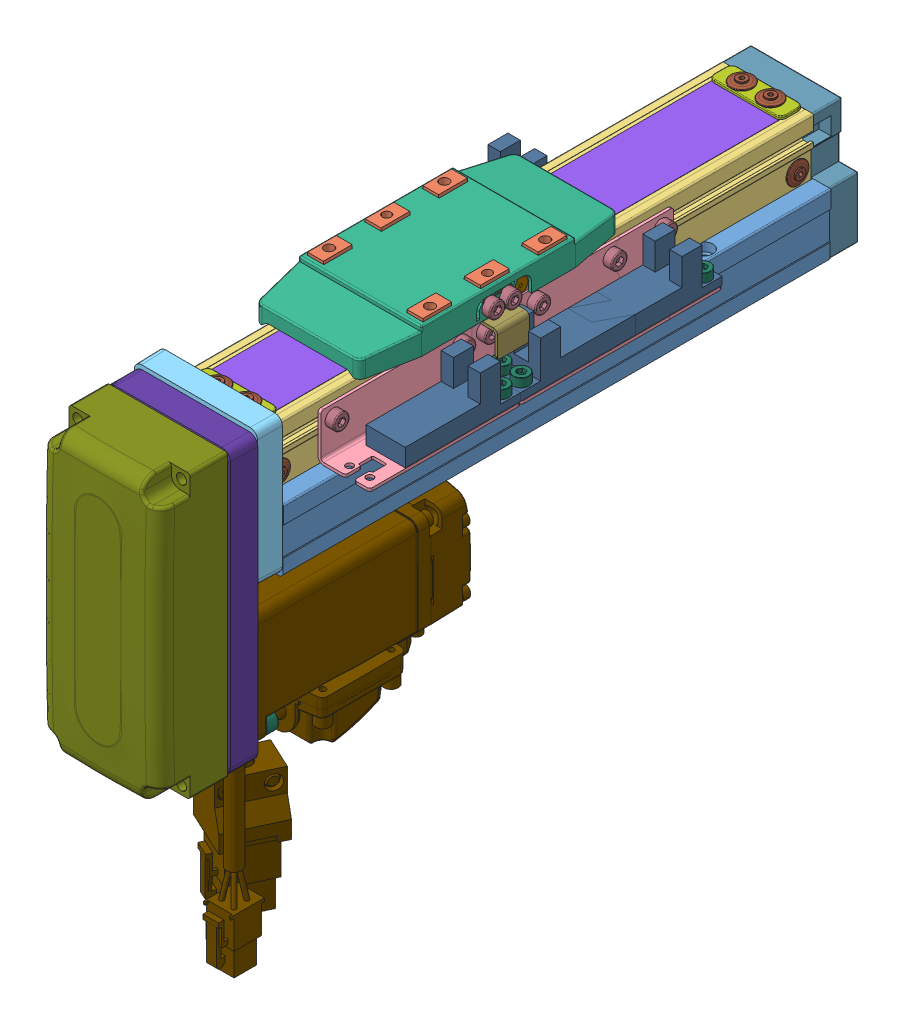
SolidWorks assembly G4-BM-100W, configuration 默认. Lengths in mm.
Overall size (67.76 184.1 242.95).
59 component instances, 18 part files, 48 mates.
Components (placement in the parent):
- 复件 底座GY4+140^G4-BM-100W-1: 复件 底座GY4+140^G4-BM-100W [默认] at (-6.4941 12.4482 0) x (-1 0 0) z (0 -1 0) size (44 190 22.05) (virtual)
- 复件 滑台G4^G4-BM-100W-1: 复件 滑台G4^G4-BM-100W [默认] at (2.1217 9 -75.2304) x (-1 0 0) z (0 0 -1) size (40 11.99 50) (virtual)
- 复件 侧盖G4+140^G4-BM-100W-1: 复件 侧盖G4+140^G4-BM-100W [默认] at (5.1767 14.25 0) x (-1 0 0) z (0 0 -1) size (8.3 20.5 190) (virtual)
- 复件 304开关座片G5-12^G4-BM-100W-1: 复件 304开关座片G5-12^G4-BM-100W [Default] at (5.9767 22.8 -18) x (0 0 -1) z (1 0 0) size (52.5 16 18) (virtual)
- 复件 丝杆座板GY4^G4-BM-100W-1: 复件 丝杆座板GY4^G4-BM-100W [默认] at (-9.9033 25 0) x (-1 0 0) z (0 0 -1) size (43 47.4 8.5) (virtual)
- 复件 滑台盖G4^G4-BM-100W-1: 复件 滑台盖G4^G4-BM-100W [默认] at (-9.9033 42.1 -120.2304) x (0 0 1) z (0 -1 0) size (90 42.6 9) (virtual)
- 复件 304钢带压片G4^G4-BM-100W-1: 复件 304钢带压片G4^G4-BM-100W [默认] at (-9.9033 41.6 -186) x (-1 0 0) z (0 0 -1) size (25 1 8) (virtual)
- 复件 钢带G4+140^G4-BM-100W-1: 复件 钢带G4+140^G4-BM-100W [Default] at (-20.8433 41.5 -581.114) x (0 0 -1) z (0 1 0) size (190 23.5 0.1) (virtual)
- 复件 304钢带压片G4^G4-BM-100W-2: 复件 304钢带压片G4^G4-BM-100W [默认] at (-9.9033 41.6 -4) x (-1 0 0) z (0 0 -1) size (25 1 8) (virtual)
- 复件 弹子油杯D5x5.5^G4-BM-100W-1: 复件 弹子油杯D5x5.5^G4-BM-100W [默认] at (-30.3783 45.5 -83.7304) x (0 0.72753 0.686076) z (1 0 0) size (5 5 5.73) (virtual)
- 复件 弹子油杯D5x5.5^G4-BM-100W-2: 复件 弹子油杯D5x5.5^G4-BM-100W [默认] at (10.6217 45.5 -83.7304) x (0 0.972647 -0.232289) z (-1 0 0) size (5 5 5.73) (virtual)
- 复件 光电开关EE-SX674^G4-BM-100W-1: 复件 光电开关EE-SX674^G4-BM-100W [默认] at (10.1767 23.8 -30.5) x (0 0 -1) z (1 0 0) size (40 15.5 13.6) (virtual)
- 复件 不锈钢内六角定制螺丝M3X7^G4-BM-100W-1: 复件 不锈钢内六角定制螺丝M3X7^G4-BM-100W [默认] at (-4.9033 42.9733 -4) x (0.724639 0 -0.689128) z (0 -1 0) size (7.67 7.67 6.5) (virtual)
- 复件 不锈钢内六角定制螺丝M3X7^G4-BM-100W-2: 复件 不锈钢内六角定制螺丝M3X7^G4-BM-100W [默认] at (-14.9033 42.9733 -4) x (0.264221 0 -0.964462) z (0 -1 0) size (7.67 7.67 6.5) (virtual)
- 复件 不锈钢内六角定制螺丝M3X7^G4-BM-100W-3: 复件 不锈钢内六角定制螺丝M3X7^G4-BM-100W [默认] at (-4.9033 42.9733 -186) x (-0.045987 0 0.998942) z (0 -1 0) size (7.67 7.67 6.5) (virtual)
- 复件 不锈钢内六角定制螺丝M3X7^G4-BM-100W-4: 复件 不锈钢内六角定制螺丝M3X7^G4-BM-100W [默认] at (-14.9033 42.9733 -186) x (0.70866 0 0.705551) z (0 -1 0) size (7.67 7.67 6.5) (virtual)
- 复件 不锈钢内六角定制螺丝M3X7^G4-BM-100W-5: 复件 不锈钢内六角定制螺丝M3X7^G4-BM-100W [默认] at (5.55 26.15 -5) x (0 0.645926 0.7634) z (-1 0 0) size (7.67 7.67 6.5) (virtual)
- 复件 不锈钢内六角定制螺丝M3X7^G4-BM-100W-6: 复件 不锈钢内六角定制螺丝M3X7^G4-BM-100W [默认] at (5.55 26.15 -185) x (0 0.430934 0.902383) z (-1 0 0) size (7.67 7.67 6.5) (virtual)
- 复件 不锈钢内六角定制螺丝M3X7^G4-BM-100W-7: 复件 不锈钢内六角定制螺丝M3X7^G4-BM-100W [默认] at (-25.3602 26.15 -185) x (0 -0.999999 -0.001479) z (1 0 0) size (7.67 7.67 6.5) (virtual)
- 复件 不锈钢内六角定制螺丝M3X7^G4-BM-100W-8: 复件 不锈钢内六角定制螺丝M3X7^G4-BM-100W [默认] at (-25.3565 26.15 -5) x (0 -1 0) z (1 0 0) size (7.67 7.67 6.5) (virtual)
- 复件 304感应片G5^G4-BM-100W-1: 复件 304感应片G5^G4-BM-100W [默认] at (15.6217 33 -80.7304) x (0 1 0) z (0 0 1) size (15 6.5 11) (virtual)
- hexagon socket head cap screws gb-32: hexagon socket head cap screws gb [GB_FASTENER_SCREWS_HSHCS M3X6-N] at (14.1217 45.5 -78.2304) x (-1 0 0) z (0 -0.928252 -0.371951) size (9 5.5 5.5)
- 复件 光电开关EE-SX674^G4-BM-100W-15: 复件 光电开关EE-SX674^G4-BM-100W [默认] at (23.7767 23.8 -110.5) x (0 0 1) z (-1 0 0) size (40 15.5 13.6) (virtual)
- 复件 304开关座片G5-12^G4-BM-100W-11: 复件 304开关座片G5-12^G4-BM-100W [Default] at (5.9767 22.8 -70.5) x (0 0 -1) z (1 0 0) size (52.5 16 18) (virtual)
- 复件 304开关座片G5-12^G4-BM-100W-10: 复件 304开关座片G5-12^G4-BM-100W [Default] at (5.9767 22.8 -88) x (0 0 -1) z (1 0 0) size (52.5 16 18) (virtual)
- 复件 轴承端盖G4(机加件)^G4-BM-100W-1: 复件 轴承端盖G4(机加件)^G4-BM-100W [默认] at (-9.9033 11.9 -190) x (0 0 -1) z (1 0 0) size (10 40.8 43) (virtual)
- hexagon socket head cap screws gb-33: hexagon socket head cap screws gb [GB_FASTENER_SCREWS_HSHCS M3X6-N] at (14.1217 45.5 -72.2304) x (-1 0 0) z (0 -0.928252 -0.371951) size (9 5.5 5.5)
- hexagon socket head cap screws gb-34: hexagon socket head cap screws gb [GB_FASTENER_SCREWS_HSHCS M3X6-N] at (-33.8783 45.5 -78.2304) x (1 0 0) z (0 0.928252 0.371951) size (9 5.5 5.5)
- hexagon socket head cap screws gb-35: hexagon socket head cap screws gb [GB_FASTENER_SCREWS_HSHCS M3X6-N] at (-33.8783 45.5 -72.2304) x (1 0 0) z (0 0.928252 0.371951) size (9 5.5 5.5)
- 复件 侧盖G4+140^G4-BM-100W-5: 复件 侧盖G4+140^G4-BM-100W [默认] at (-24.9833 14.25 -190) size (8.3 20.5 190) (virtual)
- 复件 光电开关EE-SX674^G4-BM-100W-14: 复件 光电开关EE-SX674^G4-BM-100W [默认] at (10.1767 23.8 -100.5) x (0 0 -1) z (1 0 0) size (40 15.5 13.6) (virtual)
- 复件 光电开关EE-SX674^G4-BM-100W-16: 复件 光电开关EE-SX674^G4-BM-100W [默认] at (-43.5833 23.8 -100.5) x (0 0 -1) z (1 0 0) size (40 15.5 13.6) (virtual)
- 复件 304开关座片G5-12^G4-BM-100W-14: 复件 304开关座片G5-12^G4-BM-100W [Default] at (-25.7833 22.8 -140.5) x (0 0 1) z (-1 0 0) size (52.5 16 18) (virtual)
- 复件 304感应片G5^G4-BM-100W-4: 复件 304感应片G5^G4-BM-100W [默认] at (-35.3783 33 -69.7304) x (0 1 0) z (0 0 -1) size (15 6.5 11) (virtual)
- hexagon socket head cap screws gb-36: hexagon socket head cap screws gb [GB_FASTENER_SCREWS_HSHCS M3X6-N] at (-26.4033 5.05 -199.6) x (0 0 1) z (-0.891634 -0.452757 0) size (9 5.5 5.5)
- hexagon socket head cap screws gb-37: hexagon socket head cap screws gb [GB_FASTENER_SCREWS_HSHCS M3X6-N] at (6.5967 5.05 -199.6) x (0 0 1) z (-0.891634 -0.452757 0) size (9 5.5 5.5)
- hexagon socket head cap screws gb-38: hexagon socket head cap screws gb [GB_FASTENER_SCREWS_HSHCS M3X6-N] at (-26.4033 18.05 -199.6) x (0 0 1) z (-0.891634 -0.452757 0) size (9 5.5 5.5)
- hexagon socket head cap screws gb-39: hexagon socket head cap screws gb [GB_FASTENER_SCREWS_HSHCS M3X6-N] at (6.5967 18.05 -199.6) x (0 0 1) z (-0.891634 -0.452757 0) size (9 5.5 5.5)
- hexagon socket head cap screws gb-41: hexagon socket head cap screws gb [GB_FASTENER_SCREWS_HSHCS M3X6-N] at (9.9767 34.8 -22.25) x (-1 0 0) z (0 -0.928252 -0.371951) size (9 5.5 5.5)
- hexagon socket head cap screws gb-42: hexagon socket head cap screws gb [GB_FASTENER_SCREWS_HSHCS M3X6-N] at (9.9767 34.8 -66.25) x (-1 0 0) z (0 -0.928252 -0.371951) size (9 5.5 5.5)
- hexagon socket head cap screws gb-43: hexagon socket head cap screws gb [GB_FASTENER_SCREWS_HSHCS M3X6-N] at (9.9767 34.8 -74.75) x (-1 0 0) z (0 0.928252 -0.371951) size (9 5.5 5.5)
- hexagon socket head cap screws gb-44: hexagon socket head cap screws gb [GB_FASTENER_SCREWS_HSHCS M3X6-N] at (9.9767 34.8 -118.75) x (-1 0 0) z (0 0.928252 -0.371951) size (9 5.5 5.5)
- hexagon socket head cap screws gb-45: hexagon socket head cap screws gb [GB_FASTENER_SCREWS_HSHCS M3X6-N] at (9.9767 34.8 -92.25) x (-1 0 0) z (0 -0.928252 -0.371951) size (9 5.5 5.5)
- hexagon socket head cap screws gb-46: hexagon socket head cap screws gb [GB_FASTENER_SCREWS_HSHCS M3X6-N] at (9.9767 34.8 -136.25) x (-1 0 0) z (0 -0.928252 -0.371951) size (9 5.5 5.5)
- hexagon socket head cap screws gb-47: hexagon socket head cap screws gb [GB_FASTENER_SCREWS_HSHCS M3X6-N] at (-29.7833 34.8 -136.25) x (1 0 0) z (0 0.928252 0.371951) size (9 5.5 5.5)
- hexagon socket head cap screws gb-48: hexagon socket head cap screws gb [GB_FASTENER_SCREWS_HSHCS M3X6-N] at (-29.7833 34.8 -92.25) x (1 0 0) z (0 0.928252 0.371951) size (9 5.5 5.5)
- socket head cap screw_iso-2: socket head cap screw_iso [ISO 4762 M3 x 5 --- 5N] at (13.4767 29.4 -67) x (0 -1 0) z (0 0 1) size (8 5.5 5.5)
- socket head cap screw_iso-3: socket head cap screw_iso [ISO 4762 M3 x 5 --- 5N] at (20.4767 29.4 -67) x (0 -1 0) z (0 0 1) size (8 5.5 5.5)
- socket head cap screw_iso-5: socket head cap screw_iso [ISO 4762 M4 x 12 --- 12N] at (-26.1667 -12.3383 -0.5) x (0 0 1) z (-0.923728 -0.383049 0) size (16 7 7)
- socket head cap screw_iso-6: socket head cap screw_iso [ISO 4762 M4 x 12 --- 12N] at (6.3602 -44.8652 -0.5) x (0 0 1) z (-0.815687 0.578493 0) size (16 7 7)
- socket head cap screw_iso-7: socket head cap screw_iso [ISO 4762 M3 x 5 --- 5N] at (20.4767 29.4 -74) x (0 -1 0) z (0 0 1) size (8 5.5 5.5)
- socket head cap screw_iso-8: socket head cap screw_iso [ISO 4762 M3 x 5 --- 5N] at (13.4767 29.4 -74) x (0 -1 0) z (0 0 1) size (8 5.5 5.5)
- socket head cap screw_iso-9: socket head cap screw_iso [ISO 4762 M3 x 5 --- 5N] at (13.4767 29.4 -137) x (0 -1 0) z (0 0 1) size (8 5.5 5.5)
- socket head cap screw_iso-10: socket head cap screw_iso [ISO 4762 M3 x 5 --- 5N] at (20.4767 29.4 -137) x (0 -1 0) z (0 0 1) size (8 5.5 5.5)
- socket head cap screw_iso-11: socket head cap screw_iso [ISO 4762 M3 x 5 --- 5N] at (-33.2833 29.4 -137) x (0 -1 0) z (0 0 -1) size (8 5.5 5.5)
- socket head cap screw_iso-12: socket head cap screw_iso [ISO 4762 M3 x 5 --- 5N] at (-40.2833 29.4 -137) x (0 -1 0) z (0 0 -1) size (8 5.5 5.5)
- 复件 同步轮罩壳G4^G4-BM-100W-1: 复件 同步轮罩壳G4^G4-BM-100W [默认] at (-9.9033 -2.3518 41.5) x (0 1 0) z (-1 0 0) size (98.56 24.45 42.56) (virtual)
- 复件 电机板G4-BLRM-P38^G4-BM-100W-1: 复件 电机板G4-BLRM-P38^G4-BM-100W [Default] at (-9.9033 -2.3518 -4.5) x (0 0 -1) z (1 0 0) size (10 98 43) (virtual)
- 复件 台达100W电机ECM-B3L-C20401RS1^G4-BM-100W-1: 复件 台达100W电机ECM-B3L-C20401RS1^G4-BM-100W [Default] at (-9.9033 -28.6018 3.5) x (-1 0 0) z (0 0 1) size (53.15 124.71 102.71) (virtual)
Mates (geometry in assembly coordinates):
- 重合86: coincident: plane of 复件 滑台G4^G4-BM-100W-1 through (-29.8783 50 -60.2304) normal (0 1 0); plane of 复件 滑台盖G4^G4-BM-100W-1 through (-31.2033 50 -101.4804) normal (0 -1 0)
- 同心50: concentric: cylinder of 复件 滑台G4^G4-BM-100W-1 through (-29.8783 45.5 -83.7304) axis (-1 0 0) radius 2.5; cylinder of 复件 弹子油杯D5x5.5^G4-BM-100W-1 through (-24.8783 45.5 -83.7304) axis (-1 0 0) radius 2.5
- 重合98: coincident: plane of 复件 滑台G4^G4-BM-100W-1 through (-24.8783 45.5 -83.7304) normal (-1 0 0); circle of 复件 弹子油杯D5x5.5^G4-BM-100W-1
- 同心51: concentric: cylinder of 复件 滑台G4^G4-BM-100W-1 through (10.1217 45.5 -83.7304) axis (1 0 0) radius 2.5; cylinder of 复件 弹子油杯D5x5.5^G4-BM-100W-2 through (5.1217 45.5 -83.7304) axis (1 0 0) radius 2.5
- 重合99: coincident: plane of 复件 滑台G4^G4-BM-100W-1 through (5.1217 45.5 -83.7304) normal (1 0 0); circle of 复件 弹子油杯D5x5.5^G4-BM-100W-2
- 重合127: coincident: plane of 复件 304钢带压片G4^G4-BM-100W-1 through (0.5967 42.6 -184) normal (0 1 0); circle of 复件 不锈钢内六角定制螺丝M3X7^G4-BM-100W-3
- 重合128: coincident: plane of 复件 304钢带压片G4^G4-BM-100W-1 through (0.5967 42.6 -184) normal (0 1 0); circle of 复件 不锈钢内六角定制螺丝M3X7^G4-BM-100W-4
- 同心86: concentric: circle of 复件 侧盖G4+140^G4-BM-100W-1; cylinder of 复件 不锈钢内六角定制螺丝M3X7^G4-BM-100W-6 through (0.07 26.15 -185) axis (1 0 0) radius 1.5
- 重合133: coincident: plane of 复件 侧盖G4+140^G4-BM-100W-1 through (5.1767 30.4257 -190) normal (1 0 0); circle of 复件 不锈钢内六角定制螺丝M3X7^G4-BM-100W-6
- 重合150: coincident: plane of 复件 滑台G4^G4-BM-100W-1 through (10.1217 42.5 -100.2304) normal (1 0 0); plane of 复件 304感应片G5^G4-BM-100W-1 through (10.1217 41 -69.7304) normal (-1 0 0)
- 同心103: concentric: cylinder of 复件 滑台G4^G4-BM-100W-1 through (10.1217 45.5 -78.2304) axis (1 0 0) radius 1.25; cylinder of 复件 304感应片G5^G4-BM-100W-1 through (10.1217 45.5 -78.2304) axis (-1 0 0) radius 1.7
- 同心104: concentric: cylinder of 复件 滑台G4^G4-BM-100W-1 through (10.1217 45.5 -72.2304) axis (1 0 0) radius 1.25; cylinder of 复件 304感应片G5^G4-BM-100W-1 through (10.1217 45.5 -72.2304) axis (-1 0 0) radius 1.7
- 同心105: concentric: cylinder of 复件 滑台G4^G4-BM-100W-1 through (10.1217 45.5 -78.2304) axis (1 0 0) radius 1.25; cylinder of hexagon socket head cap screws gb-32 through (5.1217 45.5 -78.2304) axis (1 0 0) radius 1.5
- 重合154: coincident: plane of 复件 304感应片G5^G4-BM-100W-1 through (11.1217 41 -69.7304) normal (1 0 0); plane of hexagon socket head cap screws gb-32 through (11.1217 45.5 -78.2304) normal (-1 0 0)
- 宽度8: width: plane of 复件 滑台盖G4^G4-BM-100W-1 through (-30.1033 42.1 -80.2804) normal (0 0 1); plane of 复件 滑台盖G4^G4-BM-100W-1 through (-30.1033 42.1 -70.1804) normal (0 0 -1); plane of 复件 滑台G4^G4-BM-100W-1 through (-29.8783 52 -70.2304) normal (0 0 1); plane of 复件 滑台G4^G4-BM-100W-1 through (-29.8783 52 -80.2304) normal (0 0 -1)
- 宽度9: width: plane of 复件 滑台G4^G4-BM-100W-1 through (-24.3783 48 -100.2304) normal (1 0 0); plane of 复件 滑台G4^G4-BM-100W-1 through (-29.8783 52 -100.2304) normal (-1 0 0); plane of 复件 滑台盖G4^G4-BM-100W-1 through (-24.1533 42.1 -70.1804) normal (-1 0 0); plane of 复件 滑台盖G4^G4-BM-100W-1 through (-30.1033 50.6 -101.4804) normal (1 0 0)
- 重合171: coincident: plane of 复件 底座GY4+140^G4-BM-100W-1 through (-31.4033 21.55 -190) normal (0 0 -1); plane of 复件 轴承端盖G4(机加件)^G4-BM-100W-1 through (-9.9033 11.9 -190) normal (0 0 1)
- 宽度10: width: plane of 复件 底座GY4+140^G4-BM-100W-1 through (12.0967 21.55 -190) normal (1 0 0); plane of 复件 底座GY4+140^G4-BM-100W-1 through (-31.9033 16.05 -190) normal (-1 0 0); plane of 复件 滑台盖G4^G4-BM-100W-1 through (-31.2033 50.6 -101.4804) normal (-1 0 0); plane of 复件 滑台盖G4^G4-BM-100W-1 through (11.3967 50.6 -101.4804) normal (1 0 0)
- 距离4: distance = 52 mm: plane of 复件 滑台G4^G4-BM-100W-1 through (-24.3783 52 -100.2304) normal (0 1 0); plane of 复件 底座GY4+140^G4-BM-100W-1 through (15.1408 0 0) normal (0 -1 0)
- 重合187: coincident: plane of 复件 底座GY4+140^G4-BM-100W-1 through (-31.4033 6.05 -190) normal (-1 0 0); plane of 复件 轴承端盖G4(机加件)^G4-BM-100W-1 through (-31.4033 11.9 -200) normal (-1 0 0)
- 同心117: concentric: cylinder of 复件 不锈钢内六角定制螺丝M3X7^G4-BM-100W-7 through (-19.8802 26.15 -185) axis (-1 0 0) radius 1.5; cylinder of 复件 侧盖G4+140^G4-BM-100W-5 through (-24.9833 26.15 -185) axis (-1 0 0) radius 1.5
- 相切3: tangent: torus of 复件 不锈钢内六角定制螺丝M3X7^G4-BM-100W-7; plane of 复件 侧盖G4+140^G4-BM-100W-5 through (-24.9833 30.4257 0) normal (-1 0 0)
- 重合189: coincident: plane of 复件 304钢带压片G4^G4-BM-100W-1 through (0.5967 41.6 -184) normal (0 -1 0); plane of 复件 钢带G4+140^G4-BM-100W-1 through (-20.8433 41.6 -581.114) normal (0 1 0)
- 同心118: concentric: cylinder of 复件 304钢带压片G4^G4-BM-100W-1 through (-4.9033 42.6 -186) axis (0 -1 0) radius 1.65; cylinder of 复件 不锈钢内六角定制螺丝M3X7^G4-BM-100W-3 through (-4.9033 37.4933 -186) axis (0 1 0) radius 1.5
- 同心119: concentric: cylinder of 复件 304钢带压片G4^G4-BM-100W-1 through (-14.9033 42.6 -186) axis (0 -1 0) radius 1.65; cylinder of 复件 不锈钢内六角定制螺丝M3X7^G4-BM-100W-4 through (-14.9033 37.4933 -186) axis (0 1 0) radius 1.5
- 重合190: coincident: plane of 复件 304钢带压片G4^G4-BM-100W-1 through (0.5967 42.6 -190) normal (0 0 -1); plane of 复件 轴承端盖G4(机加件)^G4-BM-100W-1 through (-9.9033 11.9 -190) normal (0 0 1)
- 宽度11: width: plane of 复件 304钢带压片G4^G4-BM-100W-1 through (-22.4033 42.6 -184) normal (-1 0 0); plane of 复件 304钢带压片G4^G4-BM-100W-1 through (2.5967 42.6 -184) normal (1 0 0); plane of 复件 侧盖G4+140^G4-BM-100W-1 through (5.9767 41.05 -190) normal (1 0 0); plane of 复件 侧盖G4+140^G4-BM-100W-5 through (-25.7833 41.05 0) normal (-1 0 0)
- 重合191: coincident: plane of 复件 轴承端盖G4(机加件)^G4-BM-100W-1 through (-26.4033 6.75 -196.6) normal (0 0 -1); plane of hexagon socket head cap screws gb-36 through (-26.4033 5.05 -196.6) normal (0 0 1)
- 同心121: concentric: cylinder of 复件 轴承端盖G4(机加件)^G4-BM-100W-1 through (-26.4033 5.05 -200) axis (0 0 -1) radius 1.7; cylinder of hexagon socket head cap screws gb-36 through (-26.4033 5.05 -190.6) axis (0 0 -1) radius 1.5
- 重合193: coincident: plane of 复件 304开关座片G5-12^G4-BM-100W-1 through (6.9767 40.8 -70.5) normal (1 0 0); plane of hexagon socket head cap screws gb-41 through (6.9767 34.8 -22.25) normal (-1 0 0)
- 同心123: concentric: cylinder of 复件 304开关座片G5-12^G4-BM-100W-1 through (5.9767 34.8 -22.25) axis (1 0 0) radius 1.6; cylinder of hexagon socket head cap screws gb-41 through (0.9767 34.8 -22.25) axis (1 0 0) radius 1.5
- 同心126: concentric: cylinder of 复件 光电开关EE-SX674^G4-BM-100W-1 through (13.4767 12.8 -67) axis (0 1 0) radius 1.75; cylinder of socket head cap screw_iso-2 through (13.4767 61.15 -67) axis (0 1 0) radius 2.75
- 重合196: coincident: plane of 复件 光电开关EE-SX674^G4-BM-100W-1 through (23.7767 26.4 -63.5) normal (0 1 0); plane of socket head cap screw_iso-2 through (16.2267 26.4 -67) normal (0 -1 0)
- 同心127: concentric: cylinder of 复件 光电开关EE-SX674^G4-BM-100W-1 through (20.4767 12.8 -67) axis (0 1 0) radius 1.75; cylinder of socket head cap screw_iso-3 through (20.4767 61.15 -67) axis (0 1 0) radius 2.75
- 重合197: coincident: plane of 复件 光电开关EE-SX674^G4-BM-100W-1 through (23.7767 26.4 -63.5) normal (0 1 0); plane of socket head cap screw_iso-3 through (23.2267 26.4 -67) normal (0 -1 0)
- 重合198: coincident: plane of 复件 丝杆座板GY4^G4-BM-100W-1 through (-9.9033 25 8.5) normal (0 0 1); plane of 复件 电机板G4-BLRM-P38^G4-BM-100W-1 through (-9.9033 -2.3518 8.5) normal (0 0 -1)
- 重合199: coincident: plane of 复件 同步轮罩壳G4^G4-BM-100W-1 through (-9.9033 -2.3518 18.5) normal (0 0 -1); plane of 复件 电机板G4-BLRM-P38^G4-BM-100W-1 through (-9.9033 -2.3518 18.5) normal (0 0 1)
- 同心128: concentric: cylinder of 复件 同步轮罩壳G4^G4-BM-100W-1 through (-27.9033 -48.3518 31.5) axis (0 0 1) radius 1.75; cylinder of 复件 电机板G4-BLRM-P38^G4-BM-100W-1 through (-27.9033 -48.3518 18.5) axis (0 0 1) radius 1.25
- 同心129: concentric: cylinder of 复件 同步轮罩壳G4^G4-BM-100W-1 through (8.0967 43.6482 31.5) axis (0 0 1) radius 1.75; cylinder of 复件 电机板G4-BLRM-P38^G4-BM-100W-1 through (8.0967 43.6482 18.5) axis (0 0 1) radius 1.25
- 同心130: concentric: cylinder of 复件 丝杆座板GY4^G4-BM-100W-1 through (-9.9033 25.1482 -1.5) axis (0 0 1) radius 9.2036; cylinder of 复件 电机板G4-BLRM-P38^G4-BM-100W-1 through (-9.9033 25.1482 8.5) axis (0 0 1) radius 16
- 同心131: concentric: cylinder of 复件 电机板G4-BLRM-P38^G4-BM-100W-1 through (-9.9033 -28.6018 8.5) axis (0 0 1) radius 15; cylinder of 复件 台达100W电机ECM-B3L-C20401RS1^G4-BM-100W-1 through (-9.9033 -28.6018 8.5) axis (0 0 1) radius 15
- 重合202: coincident: plane of 复件 电机板G4-BLRM-P38^G4-BM-100W-1 through (-9.9033 -2.3518 8.5) normal (0 0 -1); plane of 复件 台达100W电机ECM-B3L-C20401RS1^G4-BM-100W-1 through (10.1167 -8.5818 8.5) normal (0 0 1)
- 重合203: coincident: plane of socket head cap screw_iso-5 through (-27.5074 -9.1053 3.5) normal (0 0 1); plane of 复件 台达100W电机ECM-B3L-C20401RS1^G4-BM-100W-1 through (-22.3747 -9.2188 3.5) normal (0 0 -1)
- 同心135: concentric: cylinder of socket head cap screw_iso-5 through (-26.1667 -12.3383 -32.25) axis (0 0 -1) radius 2; cone of 复件 台达100W电机ECM-B3L-C20401RS1^G4-BM-100W-1 through (-26.1667 -12.3383 3.5) axis (0 0 -1)
- 重合204: coincident: plane of socket head cap screw_iso-6 through (8.3849 -42.0103 3.5) normal (0 0 1); plane of 复件 台达100W电机ECM-B3L-C20401RS1^G4-BM-100W-1 through (9.4796 -41.0732 3.5) normal (0 0 -1)
- 同心136: concentric: cylinder of socket head cap screw_iso-6 through (6.3602 -44.8652 -32.25) axis (0 0 -1) radius 2; cone of 复件 台达100W电机ECM-B3L-C20401RS1^G4-BM-100W-1 through (6.3602 -44.8652 3.5) axis (0 0 -1)
- 平行1: parallel: plane of 复件 底座GY4+140^G4-BM-100W-1 through (-31.9033 16.05 -190) normal (-1 0 0); plane of 复件 电机板G4-BLRM-P38^G4-BM-100W-1 through (-31.4033 -51.3518 18.5) normal (-1 0 0)
- 平行2: parallel: plane of 复件 电机板G4-BLRM-P38^G4-BM-100W-1 through (11.5967 46.6482 18.5) normal (1 0 0); plane of 复件 台达100W电机ECM-B3L-C20401RS1^G4-BM-100W-1 through (9.8467 -46.0218 -49.324) normal (1 0 0)
